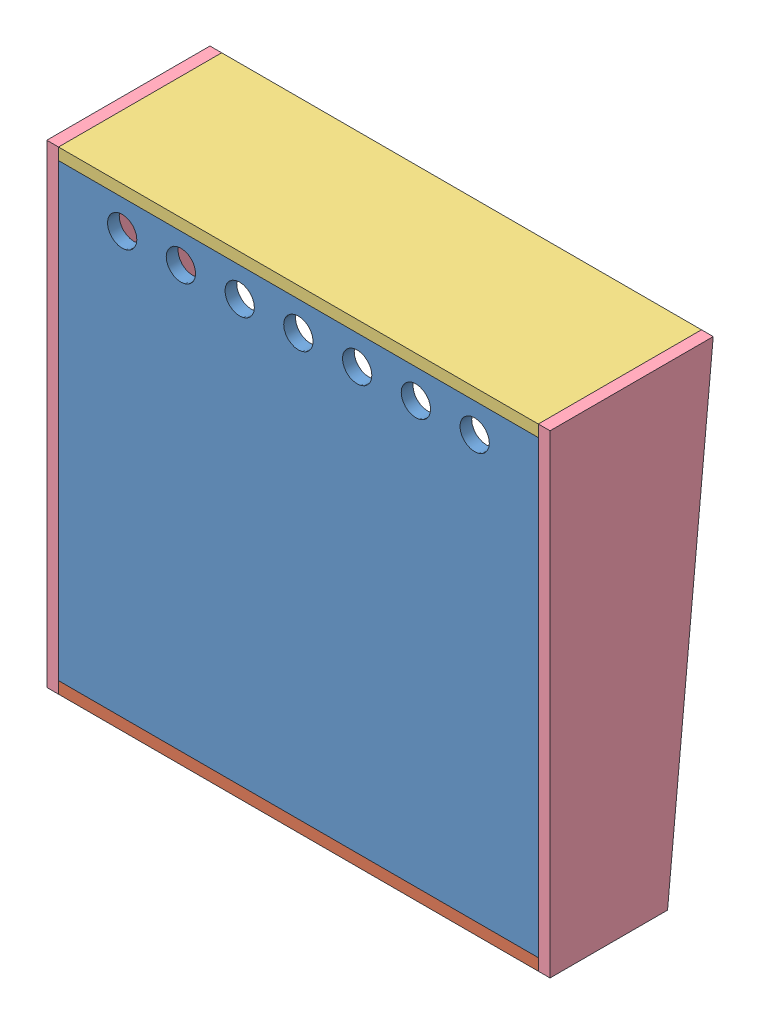
SolidWorks assembly backbox assembly 180, configuration Default. Lengths in mm.
Overall size (771 726 250).
6 component instances, 5 part files, 10 mates.
Components (placement in the parent):
- backbox back 180-1: backbox back 180 [Default] at (-152.6658 521.0455 642.0224) size (735 690 18)
- backbox bottom 180-1: backbox bottom 180 [Default] at (-152.6658 158.0455 570.0224) size (735 18 180)
- backbox top 180-1: backbox top 180 [Default] at (-152.6658 884.0455 535.0224) x (1 0 0) z (0 0 -1) size (735 18 250)
- backbox side 180-1: backbox side 180 [Default] at (-538.1658 158.0455 660.0224) size (18 726 250)
- backbox side 180-2: backbox side 180 [Default] at (214.8342 158.0455 660.0224) size (18 726 250)
- backbox panel 180-1: backbox panel 180 [Default] at (-152.6658 281.0455 498.0224) x (1 0 0) z (0 0 -1) size (735 210 18)
Mates (geometry in assembly coordinates):
- Coincident14: coincident anti-aligned: plane of backbox back 180-1 through (214.8342 176.0455 660.0224) normal (1 0 0); plane of backbox side 180-2 through (214.8342 158.0455 660.0224) normal (-1 0 0)
- Coincident16: coincident aligned: plane of backbox bottom 180-1 through (-520.1658 176.0455 660.0224) normal (0 0 1); plane of backbox side 180-1 through (-520.1658 158.0455 660.0224) normal (0 0 1)
- Coincident18: coincident anti-aligned: plane of backbox bottom 180-1 through (-520.1658 176.0455 660.0224) normal (-1 0 0); plane of backbox side 180-1 through (-520.1658 158.0455 660.0224) normal (1 0 0)
- Coincident19: coincident aligned: plane of backbox bottom 180-1 through (-152.6658 158.0455 570.0224) normal (0 -1 0); plane of backbox side 180-1 through (-520.1658 158.0455 480.0224) normal (0 -1 0)
- Coincident20: coincident anti-aligned: plane of backbox bottom 180-1 through (-152.6658 176.0455 570.0224) normal (0 1 0); plane of backbox panel 180-1 through (-520.1658 176.0455 480.0224) normal (0 -1 0)
- Coincident21: coincident aligned: plane of backbox bottom 180-1 through (-520.1658 176.0455 480.0224) normal (0 0 -1); plane of backbox panel 180-1 through (-152.6658 281.0455 480.0224) normal (0 0 -1)
- Coincident22: coincident anti-aligned: plane of backbox side 180-2 through (214.8342 158.0455 660.0224) normal (-1 0 0); plane of backbox panel 180-1 through (214.8342 386.0455 480.0224) normal (1 0 0)
- Coincident23: coincident anti-aligned: plane of backbox back 180-1 through (-520.1658 866.0455 660.0224) normal (0 1 0); plane of backbox top 180-1 through (-152.6658 866.0455 535.0224) normal (0 -1 0)
- Coincident24: coincident aligned: plane of backbox back 180-1 through (-152.6658 521.0455 660.0224) normal (0 0 1); plane of backbox top 180-1 through (-520.1658 866.0455 660.0224) normal (0 0 1)
- Coincident25: coincident anti-aligned: line of backbox top 180-1 through (-520.1658 884.0455 660.0224) axis (0 0 -1); line of backbox side 180-1 through (-520.1658 884.0455 410.0224) axis (0 0 1)
